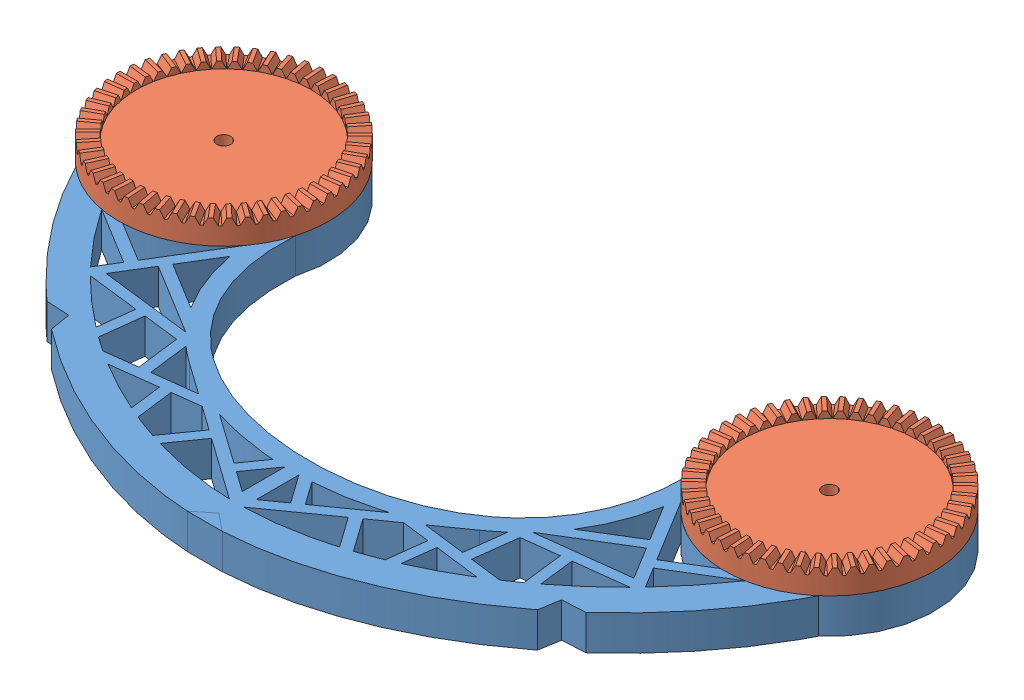
SolidWorks assembly ClubFootBraceAssembled, configuration Default. Lengths in mm.
Overall size (255.27 16.95 134.2).
3 component instances, 2 part files, 5 mates.
Components (placement in the parent):
- ClubFootBrace-3: ClubFootBrace [Default] at origin size (233 10 121.94)
- ClubFootGearM-1: ClubFootGearM [Default] at (86.5 10 10) x (-0.902191 0 0.431336) z (-0.431336 0 -0.902191) size (60 6.95 60)
- ClubFootGearM-2: ClubFootGearM [Default] at (-86.5 10 10) x (-0.766578 0 0.642151) z (-0.642151 0 -0.766578) size (60 6.95 60)
Mates (geometry in assembly coordinates):
- Concentric1: concentric aligned: cylinder of ClubFootBrace-3 through (-86.5 -0.001 10) axis (0 1 0) radius 1.75; cylinder of ClubFootGearM-2 through (-86.5 9.999 10) axis (0 1 0) radius 2
- Coincident1: coincident anti-aligned: plane of ClubFootBrace-3 through (-86.5 10 10) normal (0 1 0); plane of ClubFootGearM-2 through (-86.5 10 10) normal (0 -1 0)
- Coincident2: coincident anti-aligned: plane of ClubFootBrace-3 through (-86.5 10 10) normal (0 1 0); plane of ClubFootGearM-1 through (86.5 10 10) normal (0 -1 0)
- Concentric2: concentric aligned: cylinder of ClubFootBrace-3 through (86.5 -0.001 10) axis (0 1 0) radius 2; cylinder of ClubFootGearM-1 through (86.5 9.999 10) axis (0 1 0) radius 2
- Coincident3: coincident anti-aligned: line of ClubFootGearM-1 through (116.4914 16.95 9.2835) axis (-0.999981 0 0.006151); line of ClubFootGearM-2 through (-116.4914 16.95 10.7165) axis (0.999981 0 -0.006151)
